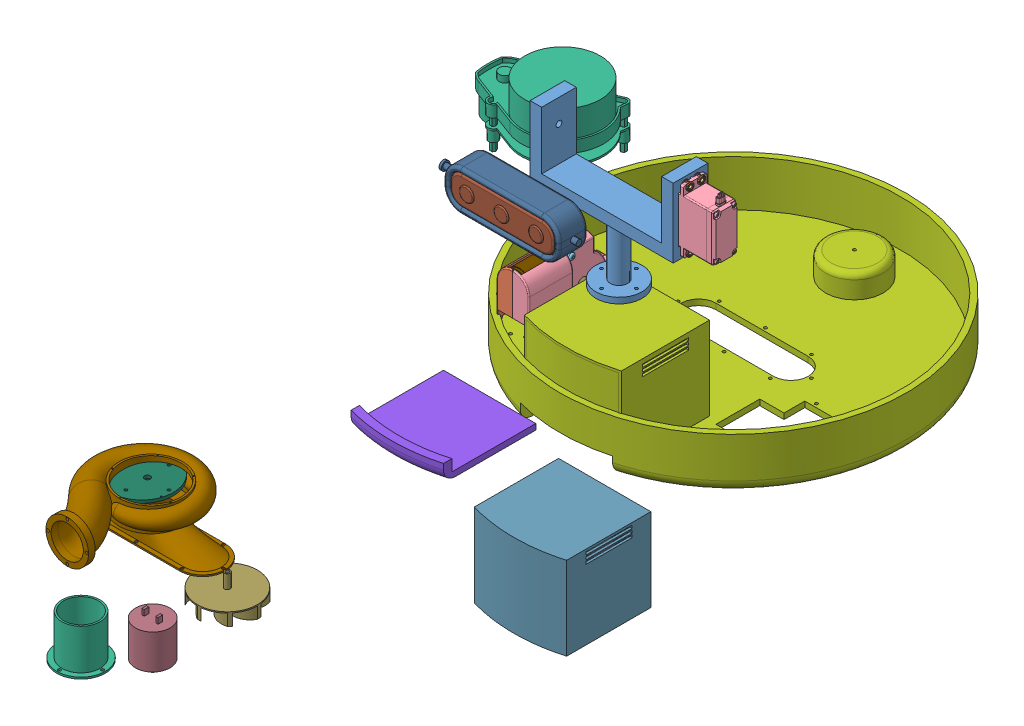
SolidWorks assembly Full Assembly, configuration Default. Lengths in mm.
Overall size (395.35 394.76 631.03).
47 component instances, 24 part files, 0 mates.
Components (placement in the parent):
- Camera Assembly (partial)-1: Camera Assembly (partial) [Default] at (54.6384 271.2018 505.045) x (-1 0 0) z (0 0 -1) size (155 115 40)
  - Camera Stand-1: Camera Stand [Default] at (-72.2568 63.5362 105.9579) size (124 115 40)
  - Servo Motor-2: Servo Motor [Default] at (-138.1568 83.4362 106.1579) x (0 1 0) z (0 0 -1) size (56.15 44.9 20.1)
    - FS5109M_Ensemble corps-1: FS5109M_Ensemble corps [Default] at origin size (56.15 39.9 20.1)
      - FS5109M_Ensemble silent-bloc-1: FS5109M_Ensemble silent-bloc [Default] at (-24.75 1.4 5) size (6.5 5.2 6.5)
        - FS5109M_silent-bloc-1: FS5109M_silent-bloc [Default] at origin size (6.5 5 6.5)
        - FS5109M_silent-bloc_douille-1: FS5109M_silent-bloc_douille [Default] at (0 -2.7 0) x (-1 0 0) z (0 0 1) size (4.5 5.2 4.5)
      - FS5109M_Ensemble silent-bloc-1-1: FS5109M_Ensemble silent-bloc-1 [Default] at (-24.75 1.4 -5) size (6.5 5.2 6.5)
        - FS5109M_silent-bloc-1: FS5109M_silent-bloc [Default] at origin size (6.5 5 6.5)
        - FS5109M_silent-bloc_douille-1: FS5109M_silent-bloc_douille [Default] at (0 -2.7 0) x (-1 0 0) z (0 0 1) size (4.5 5.2 4.5)
      - FS5109M_Ensemble silent-bloc-2-1: FS5109M_Ensemble silent-bloc-2 [Default] at (24.75 1.4 -5) x (-1 0 0) z (0 0 -1) size (6.5 5.2 6.5)
        - FS5109M_silent-bloc-1: FS5109M_silent-bloc [Default] at origin size (6.5 5 6.5)
        - FS5109M_silent-bloc_douille-1: FS5109M_silent-bloc_douille [Default] at (0 -2.7 0) x (-1 0 0) z (0 0 1) size (4.5 5.2 4.5)
      - FS5109M_Ensemble silent-bloc-3-1: FS5109M_Ensemble silent-bloc-3 [Default] at (24.75 1.4 5) x (-1 0 0) z (0 0 -1) size (6.5 5.2 6.5)
        - FS5109M_silent-bloc-1: FS5109M_silent-bloc [Default] at origin size (6.5 5 6.5)
        - FS5109M_silent-bloc_douille-1: FS5109M_silent-bloc_douille [Default] at (0 -2.7 0) x (-1 0 0) z (0 0 1) size (4.5 5.2 4.5)
      - FS5109M_corps-1: FS5109M_corps [Default] at origin size (55.35 39.9 20.1)
    - FS5109M_Ensemble arbre(2S)-1: FS5109M_Ensemble arbre(2S) [Default] at (10.1 -27.1 0) x (0.707107 0 0.707107) z (-0.707107 0 0.707107)
    - Servo Shaft-1: Servo Shaft [Default] at (10.1 11.5211 0) x (0 1 0) z (0.240131 0 -0.97074) size (15 6 6)
- LiDar-1: LiDar [Défaut] at (-103.4943 187.5217 217.6213) x (1 0 0) z (0 1 0) size (101.5 71 59)
- Bottom Cover-1: Bottom Cover [Default] at (0.0811 42.4614 173.26) size (300 77.63 300)
- Bottom Sliding Cover-1: Bottom Sliding Cover [Default] at (-60.4295 49.6406 259.2687) x (1 0 0) z (0 1 0) size (80 85.43 15.63)
- Centrifugal Pump Casing-1: Centrifugal Pump Casing [Default] at (-120.956 68.4914 556.8536) x (1 0 0) z (0 -1 0) size (119 116.73 44.75)
- Camera with Cover-1: Camera with Cover [Default] at (106.0007 377.1229 338.2427) x (-1 0 0) z (0 0 1) size (117.5 35 26)
  - Camera Cover-1: Camera Cover [Default] at (33.476 57.7203 96.1359) size (117.5 35 25)
  - Camera-1: Camera [Default] at (33.476 57.7203 95.6359) size (90 25 26)
- Centrifugal Pump Impeller-1: Centrifugal Pump Impeller [Default] at (-50.0372 35.7044 561.5084) x (1 0 0) z (0 -1 0) size (52 52 22.83)
- Centrifugal Pump Motor-1: Centrifugal Pump Motor [Default] at (-52.6014 42.478 623.6312) x (1 0 0) z (0 -1 0) size (30 30 45)
- Dust Collecting Bin-1: Dust Collecting Bin [Default] at (63.0485 27.0802 283.3103) x (-1 0 0) z (0 -1 0) size (80 78.71 72)
- Centrifugal Pump Casing Cover-1: Centrifugal Pump Casing Cover [Default] at (-140.285 66.3043 545.5722) x (1 0 0) z (0 -1 0) size (55 55 2.5)
- Motor (left)-1: Motor (left) [Default] at (1.6554 75.4614 205.2531) x (0 0 1) z (0 1 0) size (81 42.94 53)
  - Motor (left).step-1: Motor (left).step [Default] at origin size (81 42.94 53)
    - Drivning_sub_assembly_vanster_ojaobz-5.step-1: Drivning_sub_assembly_vanster_ojaobz-5.step [Default] at (359.1405 -88.75 363.0147) x (0 0 -1) z (0 1 0) size (53 81 42.94)
      - Planetbararaxel_ojaobz-5.step-1: Planetbararaxel_ojaobz-5.step [Default] at (343.5147 326.1417 9.5) x (-0.999909 0.013506 0) z (0 0 -1) size (20 20 26)
      - Planethjul_ojaobz-5.step-1: Planethjul_ojaobz-5.step [Default] at (349.0885 331.5669 9.5) x (0.33611 -0.941823 0) z (0 0 1) size (8.23 8.46 4)
      - Planethjul_ojaobz-5.step-2: Planethjul_ojaobz-5.step [Default] at (348.9399 320.5679 13.5) x (-0.820778 0.571247 0) z (0 0 -1) size (8.23 8.46 4)
      - Planethjul_ojaobz-5.step-3: Planethjul_ojaobz-5.step [Default] at (338.0895 331.7155 9.5) x (0.33611 -0.941823 0) z (0 0 1) size (8.23 8.46 4)
      - Planethjul_ojaobz-5.step-4: Planethjul_ojaobz-5.step [Default] at (337.9409 320.7165 9.5) x (0.33611 -0.941823 0) z (0 0 1) size (8.23 8.46 4)
      - Motor_drivning_ojaobz-5.step-1: Motor_drivning_ojaobz-5.step [Default] at (325.0147 279.1417 13.5) x (0 0 -1) z (0 1 0) size (24 32.5 40)
      - Snackskruv_drivning_ojaobz-5.step-1: Snackskruv_drivning_ojaobz-5.step [Default] at (325.0147 311.6417 13.5) x (0 0 -1) z (0 1 0) size (7.5 7.5 20.7)
      - Drivkapa_B_vanster_ojaobz-5.step-1: Drivkapa_B_vanster_ojaobz-5.step [Default] at (311.5147 273.1417 0) size (53 81 20.5)
      - Snackhjul_drivning_ojaobz-5.step-1: Snackhjul_drivning_ojaobz-5.step [Default] at (343.5147 326.1417 16.5) x (0.000821 -1 0) z (0 0 -1) size (33.93 33.93 10)
      - Drivkapa_A_vanster_ojaobz-5.step-1: Drivkapa_A_vanster_ojaobz-5.step [Default] at (311.5147 273.1417 28) x (-1 0 0) z (0 0 -1) size (53 81 14)
      - Skruv_blank_10_ojaobz-5.step-1: Skruv_blank_10_ojaobz-5.step [Default] at (317.5147 315.1417 22) x (0 -1 0) z (0 0 -1) size (5.6 5.6 11.94)
      - Skruv_blank_10_ojaobz-5.step-2: Skruv_blank_10_ojaobz-5.step [Default] at (340.5147 293.1417 28) x (1 0 0) z (0 0 -1) size (5.6 5.6 11.94)
      - Skruv_blank_10_ojaobz-5.step-3: Skruv_blank_10_ojaobz-5.step [Default] at (346.7647 348.1417 22) x (-0.884048 -0.467396 0) z (0 0 -1) size (5.6 5.6 11.94)
- Motor Cover-1: Motor Cover [Default] at (-105.0894 -6.52 633.2885) x (1 0 0) z (0 1 0) size (42 42 36.5)
